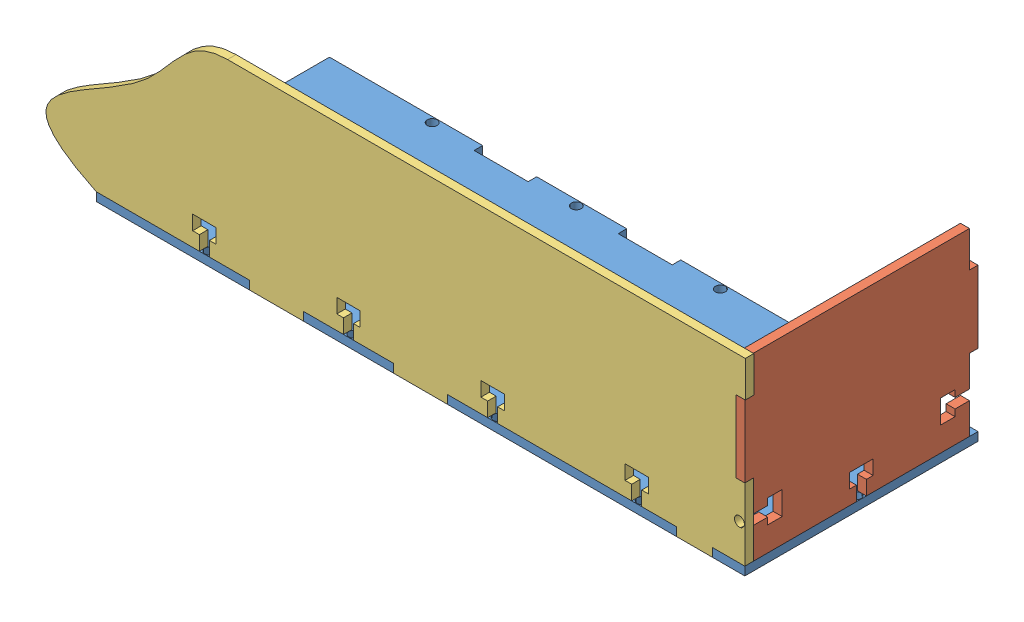
SolidWorks assembly plane2, configuration Default. Lengths in mm.
Overall size (249.43 66.5 82.2).
3 component instances, 3 part files, 6 mates.
Components (placement in the parent):
- plane_btm-1: plane_btm [Default] at (83.2603 115.0488 179.4478) size (228.6 3 82.2)
- plane_back-1: plane_back [Default] at (194.3853 149.7988 179.4478) size (3.17 63.5 82.2)
- plane_side-1: plane_side [Default] at (83.2603 149.7988 217.5478) size (249.43 66.5 3)
Mates (geometry in assembly coordinates):
- Coincident1: coincident aligned: plane of plane_btm-1 through (197.5603 118.0488 138.3478) normal (1 0 0); plane of plane_back-1 through (197.5603 149.7988 179.4478) normal (1 0 0)
- Coincident4: coincident aligned: plane of plane_btm-1 through (197.5603 118.0488 138.3478) normal (1 0 0); plane of plane_side-1 through (197.5603 131.5694 220.5478) normal (1 0 0)
- Coincident5: coincident aligned: plane of plane_btm-1 through (172.7535 118.0488 220.5478) normal (0 0 1); plane of plane_side-1 through (-28.8542 150.8218 220.5478) normal (0 0 1)
- Coincident6: coincident aligned: plane of plane_btm-1 through (83.2603 115.0488 179.4478) normal (0 -1 0); plane of plane_side-1 through (173.4303 115.0488 220.5478) normal (0 -1 0)
- Coincident7: coincident anti-aligned: plane of plane_btm-1 through (83.2603 118.0488 179.4478) normal (0 1 0); plane of plane_back-1 through (197.5603 118.0488 217.5478) normal (0 -1 0)
- Coincident8: coincident aligned: plane of plane_back-1 through (197.5603 168.8488 220.5478) normal (0 0 1); plane of plane_side-1 through (-28.8542 150.8218 220.5478) normal (0 0 1)
